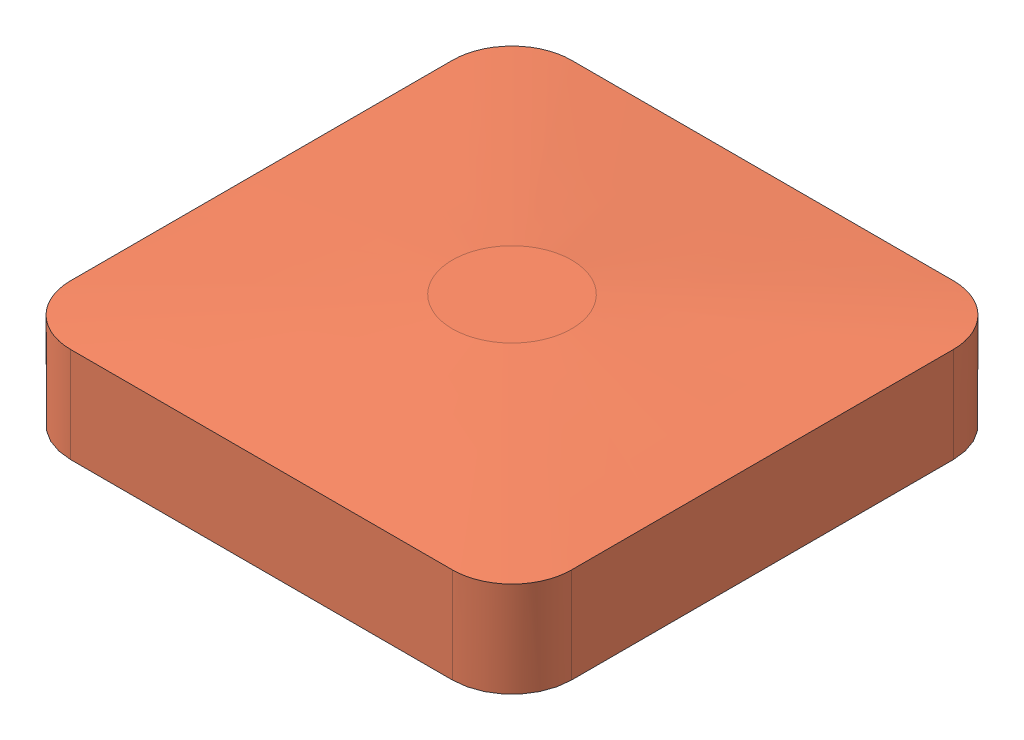
SolidWorks assembly RED, configuration Default. Lengths in mm.
Overall size (42 9.51 42).
2 component instances, 2 part files, 3 mates.
Components (placement in the parent):
- red lower-1: red lower [Default] at origin size (38.4 6.5 38.4)
- red upper-1: red upper [Default] at (-40.2 8 40.2) x (1 0 0) z (0 0 -1) size (42 9.51 42)
Mates (geometry in assembly coordinates):
- Width1: width aligned: plane of red upper-1 through (-40.2 0 40.2) normal (0 0 1); plane of red lower-1 through (1.8 0 -1.8) normal (0 0 -1); plane of red upper-1 through (0 6.5 38.4) normal (0 0 1); plane of red lower-1 through (0 6.5 0) normal (0 0 -1)
- Width2: width anti-aligned: plane of red upper-1 through (1.8 0 40.2) normal (1 0 0); plane of red lower-1 through (-40.2 0 -1.8) normal (-1 0 0); plane of red upper-1 through (-38.4 6.5 0) normal (-1 0 0); plane of red lower-1 through (0 6.5 0) normal (1 0 0)
- Coincident1: coincident aligned: plane of red lower-1 through (0 0 0) normal (0 -1 0); plane of red upper-1 through (-40.2 0 40.2) normal (0 -1 0)
